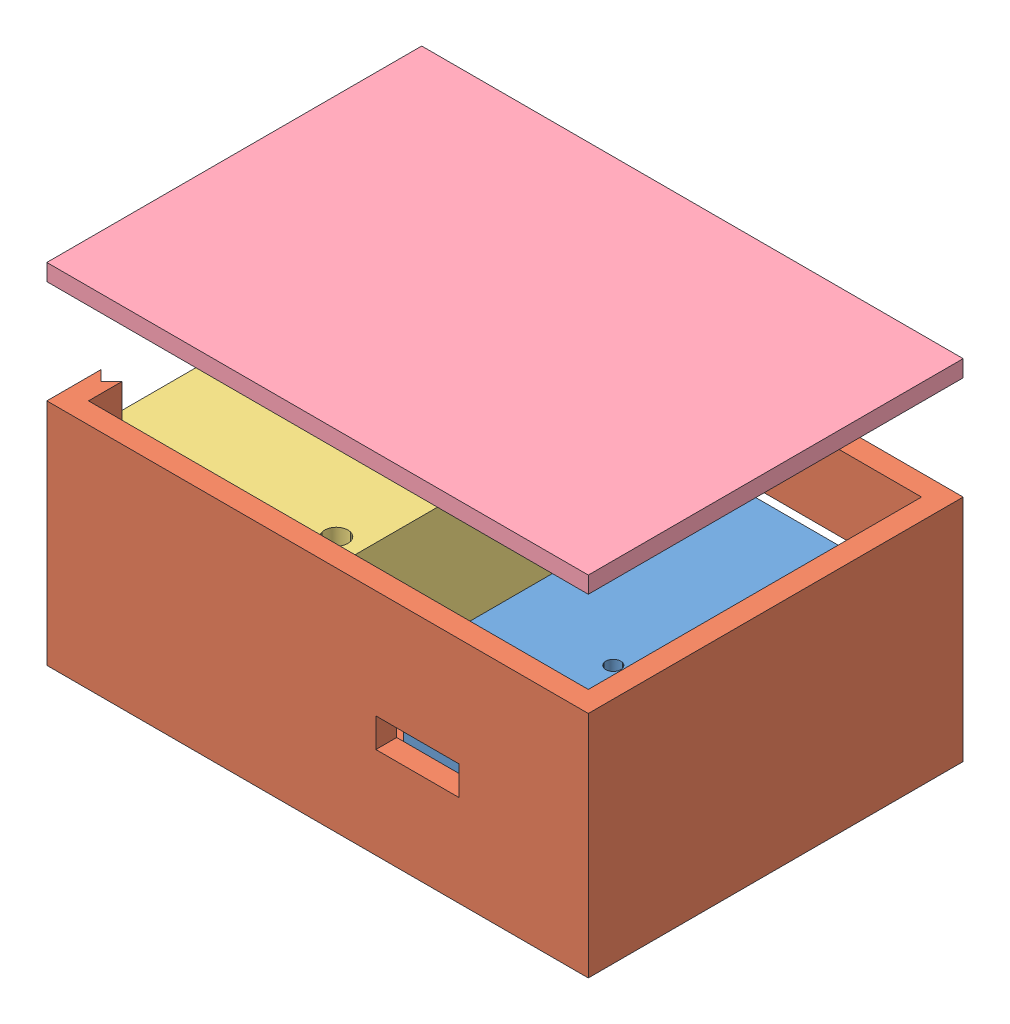
SolidWorks assembly test_asm, configuration 默认. Lengths in mm.
Overall size (65 41.89 45).
4 component instances, 4 part files, 12 mates.
Components (placement in the parent):
- sbus_ttl_board-1: sbus_ttl_board [默认] at (17.3 7.5 0) size (21 11 38)
- shell_bottom-1: shell_bottom [默认] at origin size (65 27.5 45)
- ttl_232_board-1: ttl_232_board [默认] at (-18 7.5 0) x (0 0 -1) z (1 0 0) size (32 14.5 29)
- shell_top-1: shell_top [默认] at (0 41.8904 0) x (1 0 0) z (0 0 -1) size (65 7.2 45)
Mates (geometry in assembly coordinates):
- 重合1: coincident aligned: plane of shell_bottom-1 through (0 0 0) normal (0 0 1)
- 重合2: coincident aligned: plane of shell_bottom-1 through (0 0 0) normal (0 1 0)
- 重合3: coincident aligned: plane of shell_bottom-1 through (0 0 0) normal (1 0 0)
- 同心1: concentric anti-aligned: cylinder of shell_bottom-1 through (-6.5 7.5 -13.75) axis (0 -1 0) radius 1.25; cylinder of ttl_232_board-1 through (-6.5 7.5 -13.75) axis (0 1 0) radius 1.4
- 同心2: concentric anti-aligned: cylinder of shell_bottom-1 through (-6.5 7.5 13.75) axis (0 -1 0) radius 1.25; cylinder of ttl_232_board-1 through (-6.5 7.5 13.75) axis (0 1 0) radius 1.4
- 重合4: coincident anti-aligned: plane of shell_bottom-1 through (-6.5 7.5 -13.75) normal (0 1 0); plane of ttl_232_board-1 through (-18 7.5 0) normal (0 -1 0)
- 同心3: concentric anti-aligned: cylinder of sbus_ttl_board-1 through (20 7.5 7) axis (0 1 0) radius 0.9; cylinder of shell_bottom-1 through (20 7.5 7) axis (0 -1 0) radius 0.75
- 重合5: coincident anti-aligned: plane of sbus_ttl_board-1 through (17.3 7.5 0) normal (0 -1 0); plane of shell_bottom-1 through (20 7.5 7) normal (0 1 0)
- 平行1: parallel aligned: plane of sbus_ttl_board-1 through (6.8 18.5 -19) normal (-1 0 0); plane of shell_bottom-1 through (30 27.5 -22.5) normal (-1 0 0)
- 重合6: coincident anti-aligned: plane of shell_bottom-1 through (-31.25 4.7049 17.25) normal (0.707107 0 -0.707107); plane of shell_top-1 through (-32.5 34.6904 16) normal (-0.707107 0 0.707107)
- 平行2: parallel anti-aligned: plane of ttl_232_board-1 through (-18 22 0) normal (0 1 0); plane of shell_top-1 through (0 34.6904 0) normal (0 -1 0)
- 重合8: coincident anti-aligned: plane of shell_bottom-1 through (-32.5 4.7049 -16) normal (0.707107 0 0.707107); plane of shell_top-1 through (-32.5 34.6904 -16) normal (-0.707107 0 -0.707107)
